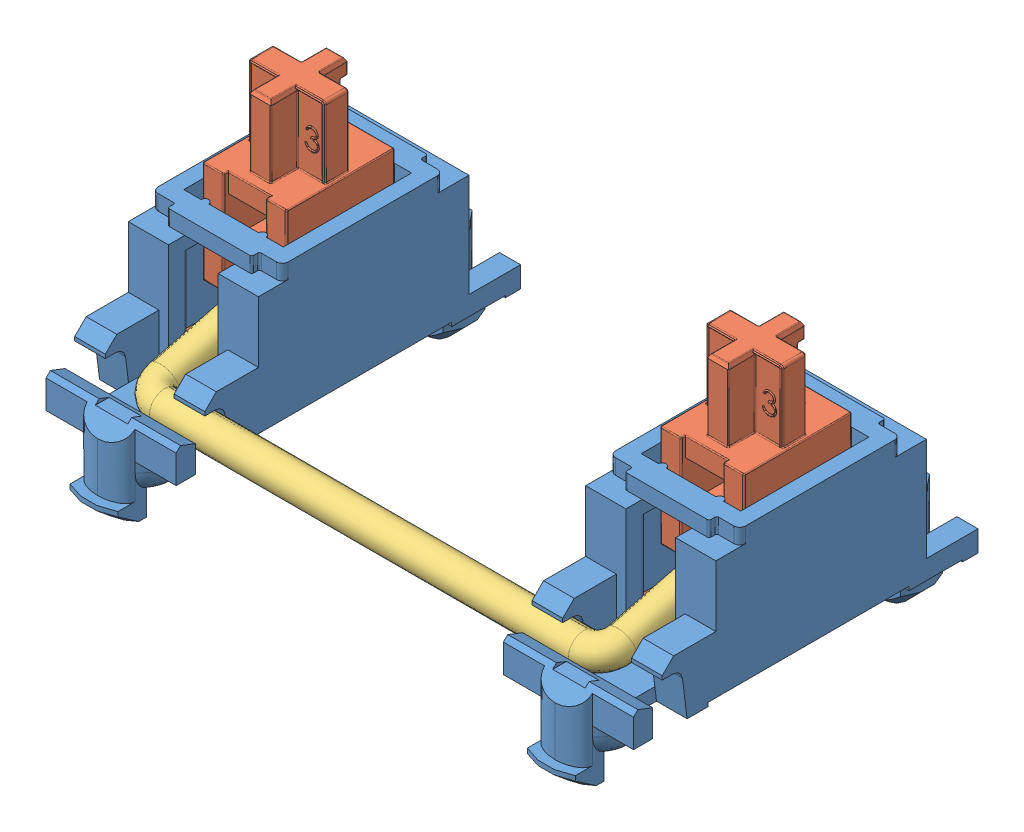
SolidWorks assembly Cherry MX Stabilizer, configuration Default. Lengths in mm.
Overall size (30.7 14.96 19.2).
5 component instances, 3 part files, 8 mates.
Components (placement in the parent):
- mx Stabilizer base 16828-1: mx Stabilizer base 16828 [Default] at origin size (6.8 10.1 19.2)
- mx Stabilizer key 16828-1: mx Stabilizer key 16828 [Default] at (0 4.757 0) size (4.41 11.95 8.3)
- metal stick 16828-1: metal stick 16828 [Default] at (11.95 0.6706 -3.0582) x (1 0 0) z (0 -0.243034 0.970018) size (25.5 1.6 12.2)
- mx Stabilizer base 16828-2: mx Stabilizer base 16828 [Default] at (23.9 0 0) size (6.8 10.1 19.2)
- mx Stabilizer key 16828-2: mx Stabilizer key 16828 [Default] at (23.9 4.757 0) size (4.41 11.95 8.3)
Mates (geometry in assembly coordinates):
- Coincident1: coincident aligned: plane of mx Stabilizer key 16828-1 through (0 4.757 0) normal (1 0 0); plane of assembly through (0 0 0) normal (1 0 0)
- Coincident2: coincident aligned: plane of mx Stabilizer key 16828-1 through (0 4.757 0) normal (0 0 1); plane of assembly through (0 0 0) normal (0 0 1)
- Coincident3: coincident aligned: plane of metal stick 16828-1 through (0 0.6706 -3.0582) normal (1 0 0); plane of assembly through (0 0 0) normal (1 0 0)
- Tangent1: tangent anti-aligned: plane of mx Stabilizer base 16828-1 through (0 -2.9 10.5) normal (0 1 0); cylinder of metal stick 16828-1 through (22.9 -2.1 8) axis (-1 0 0) radius 0.8
- Tangent2: tangent anti-aligned: plane of mx Stabilizer base 16828-1 through (3.4 -3.6 8.8) normal (0 0 -1); cylinder of metal stick 16828-1 through (22.9 -2.1 8) axis (-1 0 0) radius 0.8
- Tangent3: tangent: line of mx Stabilizer key 16828-1 through (-1.1 0.757 -0.1115) axis (1 0 0); cylinder of metal stick 16828-1 through (0 -1.857 7.03) axis (0 0.243034 -0.970018) radius 0.8
- LimitDistance1: limit distance = 3.343 mm anti-aligned: plane of mx Stabilizer base 16828-1 through (3.4 2.1 5.5) normal (0 -1 0); plane of mx Stabilizer key 16828-1 through (0 -1.243 0) normal (0 1 0)
- LimitDistance2: limit distance = 0.107 mm aligned: plane of mx Stabilizer key 16828-1 through (0.45 -3.493 -3.8) normal (0 -1 0); plane of mx Stabilizer base 16828-1 through (3.4 -3.6 -4.6) normal (0 -1 0)
